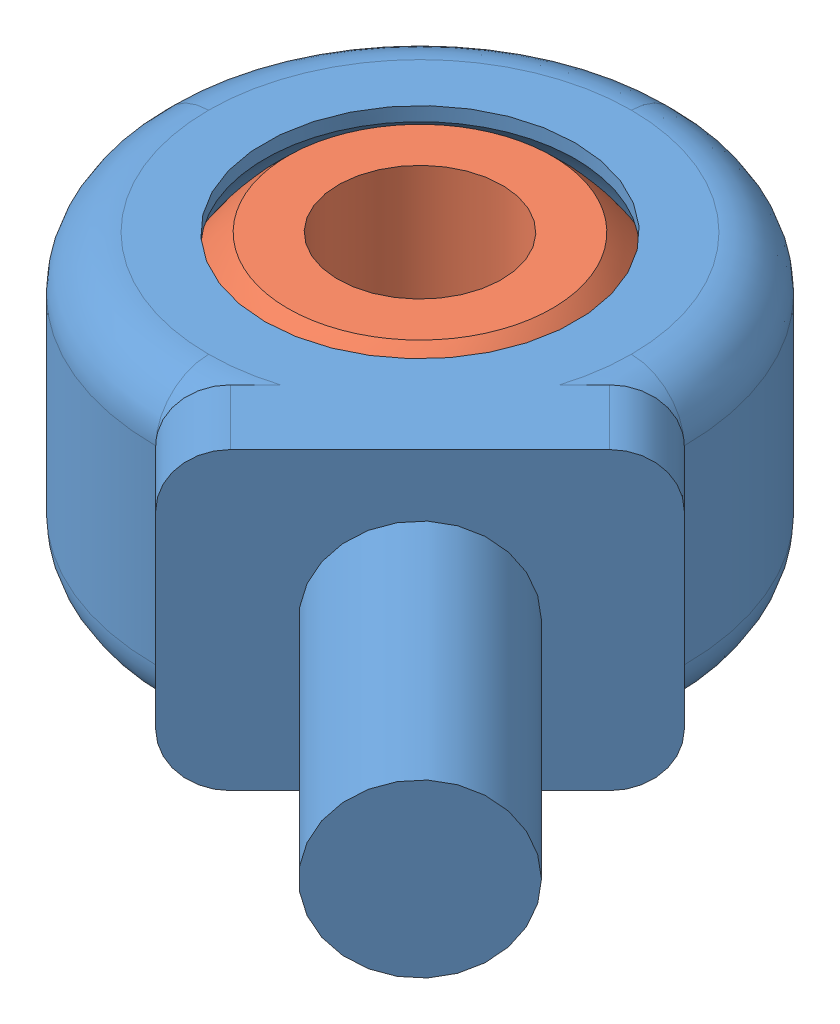
SolidWorks assembly myrodend, configuration Default. Lengths in mm.
Overall size (27.9 11.18 27.9).
2 component instances, 2 part files, 2 mates.
Components (placement in the parent):
- housing-1: housing [Default] at origin size (27.9 11.18 27.9)
- Ball-1: Ball [Default] at (-10 5.59 -10) x (0.999657 0 0.026198) z (-0.026198 0 0.999657) size (15 11.18 15)
Mates (geometry in assembly coordinates):
- Concentric2: concentric: sphere of housing-1; sphere of Ball-1
- Coincident1: coincident aligned: plane of housing-1 through (0 11.18 0) normal (0 1 0); plane of Ball-1 through (-10 11.1802 -10) normal (0 1 0)
